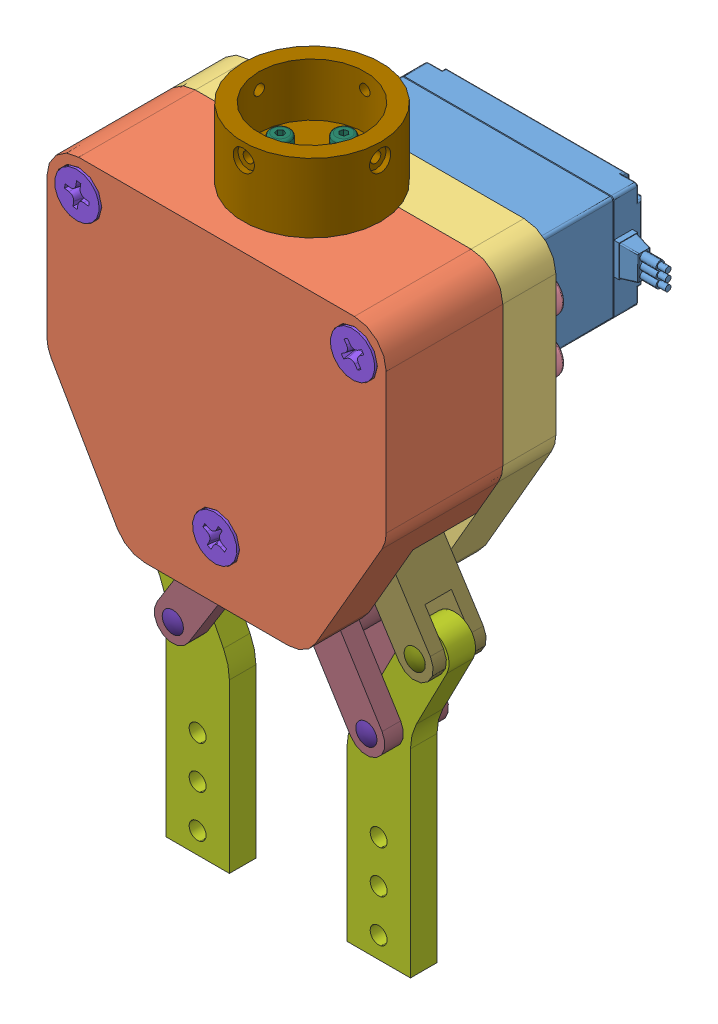
SolidWorks assembly Сборка схват, configuration По умолчанию. Lengths in mm.
Overall size (78.28 129.29 61.42).
45 component instances, 18 part files, 105 mates.
Components (placement in the parent):
- MG995-1: MG995 [По умолчанию] at origin size (55.5 20 44.57)
- Корпус 2-1: Корпус 2 [По умолчанию] at (-31.9999 21 61.0656) x (1 0 0) z (0 0 -1) size (64 60 22)
- 1-1: 1 [По умолчанию] at (32 21 29.0656) x (-1 0 0) z (0 0 1) size (64 60 10)
- DIN912-M4x12-1: DIN912-M4x12 [По умолчанию] at (-24 -5 22.8) x (0 0 1) z (-0.537932 -0.842988 0) size (16.28 7 7)
- DIN912-M4x12-2: DIN912-M4x12 [По умолчанию] at (24 5 22.8) x (0 0 1) z (-0.298401 0.954441 0) size (16.28 7 7)
- DIN912-M4x12-3: DIN912-M4x12 [По умолчанию] at (-24 5 22.8) x (0 0 1) z (-0.927261 0.374416 0) size (16.28 7 7)
- DIN912-M4x12-4: DIN912-M4x12 [По умолчанию] at (24 -5 22.8) x (0 0 1) z (-0.721763 -0.69214 0) size (16.28 7 7)
- DIN934-M4-2: DIN934-M4 [По умолчанию] at (-24 5 34.5656) size (7.43 8.21 3.68)
- DIN934-M4-3: DIN934-M4 [По умолчанию] at (24 5 34.5656) size (7.43 8.21 3.68)
- DIN934-M4-4: DIN934-M4 [По умолчанию] at (24 -5 34.5656) size (7.43 8.21 3.68)
- DIN934-M4-5: DIN934-M4 [По умолчанию] at (-24 -5 34.5656) size (7.43 8.21 3.68)
- DIN7 D5-L30-1: DIN7 D5-L30 [По умолчанию] at (12.0501 -18 33.0656) x (0 0 1) z (-0.049842 0.998757 0) size (24 5 5)
- DIN7 D5-L30-2: DIN7 D5-L30 [По умолчанию] at (-12.05 -18 33.0656) x (0 0 1) z (0.952169 -0.305572 0) size (24 5 5)
- 6_GRIPPER_ARM-1: 6_GRIPPER_ARM [По умолчанию] at (17.0771 -95.2932 47.5656) x (1 0 0) z (0 1 0) size (19.3 5 59)
- 6_GRIPPER_ARM-2: 6_GRIPPER_ARM [По умолчанию] at (-17.0771 -95.2932 42.5656) x (-1 0 0) z (0 1 0) size (19.3 5 59)
- DIN7046-1_M4x30-1: DIN7046-1_M4x30 [По умолчанию] at (26.0001 15 61.4156) x (0 0 -1) z (0.831237 0.555919 0) size (33.09 8.4 8.4)
- DIN7046-1_M4x30-2: DIN7046-1_M4x30 [По умолчанию] at (0 -28 61.4156) x (0 0 -1) z (0.888568 -0.458744 0) size (33.09 8.4 8.4)
- DIN7046-1_M4x30-3: DIN7046-1_M4x30 [По умолчанию] at (-26 15 61.4156) x (0 0 -1) z (0.988915 -0.148483 0) size (33.09 8.4 8.4)
- DIN934-M4-6: DIN934-M4 [По умолчанию] at (-26 15 29.0656) size (7.43 8.21 3.68)
- DIN934-M4-7: DIN934-M4 [По умолчанию] at (26 15 32.2656) x (0.467399 -0.884046 0) z (0 0 -1) size (7.43 8.21 3.68)
- DIN934-M4-8: DIN934-M4 [По умолчанию] at (0 -28 29.0656) size (7.43 8.21 3.68)
- ФланецСхват-1: ФланецСхват [По умолчанию] at (0.0001 34 43.0656) x (0 -1 0) z (1 0 0) size (13 26 26)
- втулка-2: втулка [По умолчанию] at (12.0501 -18 33.0656) x (0.999914 -0.013116 0) z (0 0 1) size (10 10 7)
- втулка-3: втулка [По умолчанию] at (-12.05 -18 57.0656) x (0.833208 -0.552959 0) z (0 0 -1) size (10 10 7)
- втулка-4: втулка [По умолчанию] at (12.0501 -18 57.0656) x (0.99444 0.105308 0) z (0 0 -1) size (10 10 7)
- втулка-6: втулка [По умолчанию] at (-12.05 -18 33.0656) x (0.948132 0.317878 0) z (0 0 1) size (10 10 7)
- ВалШестерня-3: ВалШестерня [Вал-шестерня] at (10 0 44.5) x (0 0 1) z (0.822261 0.56911 0) size (10 13.61 13.61)
- КолесоКривошип-1: КолесоКривошип [Колесо-кривошип] at (12.0501 -18 44.0656) x (0 0 1) z (0.841252 0.540643 0) size (10 42.92 25.84)
- КолесоКривошип-2: КолесоКривошип [Колесо-кривошип] at (-12.05 -18 44.0656) x (0 0 1) z (0.841251 -0.540644 0) size (10 42.92 25.84)
- Кривошип-1: Кривошип [По умолчанию] at (-21.2278 -54.2097 39.0656) x (0 0 1) z (-0.848527 0.529152 0) size (12 33 7)
- Кривошип-2: Кривошип [По умолчанию] at (15.2881 -57.9138 39.0656) x (0 0 1) z (-0.848528 -0.52915 0) size (12 33 7)
- gayka_m2-1: gayka_m2 [По умолчанию] at (0 13.4 37.0656) x (0.888267 0 -0.459328) z (0 1 0) size (4.25 4.76 2.06)
- gayka_m2-2: gayka_m2 [По умолчанию] at (0.0001 13.4 49.0656) x (0.888267 0 -0.459328) z (0 1 0) size (4.25 4.76 2.06)
- gayka_m2-3: gayka_m2 [По умолчанию] at (-5.9999 13.4 43.0656) x (0.888267 0 -0.459328) z (0 1 0) size (4.25 4.76 2.06)
- gayka_m2-5: gayka_m2 [По умолчанию] at (6.0001 13.4 43.0656) x (0.888267 0 -0.459328) z (0 1 0) size (4.25 4.76 2.06)
- DIN912-M2x12-1: DIN912-M2x12 [По умолчанию] at (6.0001 26 43.0656) x (0 -1 0) z (0.6502 0 0.759763) size (14.19 3.8 3.8)
- DIN912-M2x12-2: DIN912-M2x12 [По умолчанию] at (0.0001 26 37.0656) x (0 -1 0) z (0.733895 0 0.679263) size (14.19 3.8 3.8)
- DIN912-M2x12-3: DIN912-M2x12 [По умолчанию] at (-5.9999 26 43.0656) x (0 -1 0) z (0.223689 0 0.97466) size (14.19 3.8 3.8)
- DIN912-M2x12-4: DIN912-M2x12 [По умолчанию] at (0.0001 26 49.0656) x (0 -1 0) z (0.998157 0 0.060686) size (14.19 3.8 3.8)
- DIN7 D4-L10-1: DIN7 D4-L10 [По умолчанию] at (-26.3771 -40.2932 40.0656) x (0 0 1) z (-1 0 0) size (11.2 4 4)
- DIN7 D4-L10-2: DIN7 D4-L10 [По умолчанию] at (26.3771 -40.2932 40.0656) x (0 0 1) z (-1 0 0) size (11.2 4 4)
- DIN7 D4-L12-7: DIN7 D4-L12 [По умолчанию] at (-18.258 -56.0617 39.0656) x (0 0 1) z (-0.999999 0.001325 0) size (13.2 4 4)
- DIN7 D4-L12-8: DIN7 D4-L12 [По умолчанию] at (18.258 -56.0617 39.0656) x (0 0 1) z (-0.999999 0.001325 0) size (13.2 4 4)
- DIN7 D4-L24-1: DIN7 D4-L24 [По умолчанию] at (4.5001 -34 33.0656) x (0 0 1) z (0.845277 -0.534328 0) size (25.2 4 4)
- DIN7 D4-L24-2: DIN7 D4-L24 [По умолчанию] at (-4.5 -34 33.0656) x (0 0 1) z (-0.548806 -0.83595 0) size (25.2 4 4)
Mates (geometry in assembly coordinates):
- Концентричный5: concentric aligned: circle of MG995-1; circle of 1-1
- Концентричный6: concentric aligned: circle of MG995-1; circle of 1-1
- Концентричный13: concentric aligned: circle of DIN912-M4x12-3; circle of MG995-1
- Концентричный14: concentric aligned: circle of MG995-1; circle of DIN912-M4x12-2
- Концентричный16: concentric aligned: circle of MG995-1; circle of DIN912-M4x12-4
- Концентричный18: concentric anti-aligned: circle of 1-1; circle of DIN934-M4-2
- Совпадение19: coincident anti-aligned: plane of 1-1 through (32 21 34.5656) normal (0 0 1); plane of DIN934-M4-2 through (-24 5 34.5656) normal (0 0 -1)
- Параллельность4: parallel anti-aligned: plane of 1-1 through (-27.6 2.9215 34.5656) normal (1 0 0); plane of DIN934-M4-2 through (-27.5 6.9795 37.7656) normal (-1 0 0)
- Параллельность8: parallel anti-aligned: plane of 1-1 through (-27.6 -7.0785 34.5656) normal (1 0 0); plane of DIN934-M4-5 through (-27.5 -3.0205 37.7656) normal (-1 0 0)
- Совпадение32: coincident anti-aligned: plane of 1-1 through (32 21 34.5656) normal (0 0 1); plane of DIN934-M4-5 through (-24 -5 34.5656) normal (0 0 -1)
- Концентричный22: concentric anti-aligned: circle of 1-1; circle of DIN934-M4-5
- Концентричный23: concentric anti-aligned: cylinder of MG995-1 through (-24 -5 29) axis (0 0 -1) radius 2; circle of DIN912-M4x12-1
- Совпадение35: coincident anti-aligned: plane of 1-1 through (32 21 34.5656) normal (0 0 1); plane of DIN934-M4-3 through (24 5 34.5656) normal (0 0 -1)
- Концентричный24: concentric anti-aligned: circle of 1-1; circle of DIN934-M4-3
- Совпадение37: coincident anti-aligned: plane of 1-1 through (32 21 34.5656) normal (0 0 1); plane of DIN934-M4-4 through (24 -5 34.5656) normal (0 0 -1)
- Концентричный25: concentric anti-aligned: circle of 1-1; circle of DIN934-M4-4
- Параллельность11: parallel anti-aligned: plane of 1-1 through (27.6 7.0785 34.5656) normal (-1 0 0); plane of DIN934-M4-3 through (27.5 3.0205 37.7656) normal (1 0 0)
- Параллельность12: parallel anti-aligned: plane of 1-1 through (27.6 -2.9215 34.5656) normal (-1 0 0); plane of DIN934-M4-4 through (27.5 -6.9795 37.7656) normal (1 0 0)
- Совпадение47: coincident anti-aligned: plane of Корпус 2-1 through (-31.9999 21 39.0656) normal (0 0 -1); plane of 1-1 through (32 21 39.0656) normal (0 0 1)
- Концентричный31: concentric aligned: circle of Корпус 2-1; circle of 1-1
- Концентричный32: concentric aligned: circle of Корпус 2-1; circle of 1-1
- Концентричный33: concentric aligned: circle of Корпус 2-1; circle of DIN7046-1_M4x30-3
- Концентричный34: concentric aligned: circle of Корпус 2-1; circle of DIN7046-1_M4x30-2
- Концентричный35: concentric aligned: circle of Корпус 2-1; circle of DIN7046-1_M4x30-1
- Параллельность13: parallel anti-aligned: plane of 1-1 through (-22.4 17.0785 32.2656) normal (-1 0 0); plane of DIN934-M4-6 through (-22.5 13.0205 32.2656) normal (1 0 0)
- Концентричный36: concentric anti-aligned: circle of 1-1; circle of DIN934-M4-6
- Совпадение58: coincident anti-aligned: plane of 1-1 through (32 21 32.2656) normal (0 0 -1); plane of DIN934-M4-6 through (-26 15 32.2656) normal (0 0 1)
- Совпадение59: coincident anti-aligned: plane of 1-1 through (32 21 32.2656) normal (0 0 -1); plane of DIN934-M4-7 through (26 15 32.2656) normal (0 0 1)
- Концентричный38: concentric aligned: circle of 1-1; circle of DIN934-M4-7
- Параллельность14: parallel anti-aligned: plane of 1-1 through (29.6 17.0785 32.2656) normal (-1 0 0); plane of DIN934-M4-7 through (29.3859 16.7901 29.0656) normal (1 0 0)
- Совпадение62: coincident anti-aligned: plane of 1-1 through (32 21 32.2656) normal (0 0 -1); plane of DIN934-M4-8 through (0 -28 32.2656) normal (0 0 1)
- Концентричный39: concentric anti-aligned: circle of 1-1; circle of DIN934-M4-8
- Параллельность15: parallel anti-aligned: plane of 1-1 through (3.6 -25.9215 32.2656) normal (-1 0 0); plane of DIN934-M4-8 through (3.5 -29.9795 32.2656) normal (1 0 0)
- Концентричный56: concentric anti-aligned: cylinder of 1-1 through (-12.05 -18 39.0656) axis (0 0 1) radius 3.5; cylinder of DIN7 D5-L30-2 through (-12.05 -18 33.0656) axis (0 0 -1) radius 2.5
- Совпадение112: coincident anti-aligned: circle of MG995-1; circle of ВалШестерня-3
- Концентричный66: concentric anti-aligned: circle of 6_GRIPPER_ARM-2; circle of КолесоКривошип-2
- Концентричный71: concentric aligned: cylinder of 6_GRIPPER_ARM-1 through (26.3771 -40.2932 47.5656) axis (0 0 1) radius 2; cylinder of КолесоКривошип-1 through (26.3771 -40.2932 50.0656) axis (0 0 1) radius 2
- Совпадение118: coincident anti-aligned: plane of 6_GRIPPER_ARM-1 through (21.0771 -63.6799 47.5656) normal (0 0 1); plane of КолесоКривошип-1 through (18.481 -51.9056 47.5656) normal (0 0 -1)
- Совпадение120: coincident anti-aligned: plane of 1-1 through (32 21 39.0656) normal (0 0 1); plane of Кривошип-1 through (-18.258 -56.0617 39.0656) normal (0 0 -1)
- Концентричный74: concentric anti-aligned: circle of 6_GRIPPER_ARM-2; circle of Кривошип-1
- Совпадение125: coincident anti-aligned: plane of 1-1 through (32 21 39.0656) normal (0 0 1); plane of Кривошип-2 through (18.258 -56.0617 39.0656) normal (0 0 -1)
- Концентричный76: concentric aligned: circle of 6_GRIPPER_ARM-1; circle of Кривошип-2
- Концентричный77: concentric anti-aligned: circle of 6_GRIPPER_ARM-2; circle of КолесоКривошип-2
- Концентричный78: concentric anti-aligned: circle of 6_GRIPPER_ARM-2; circle of КолесоКривошип-2
- Параллельность18: parallel anti-aligned: plane of 6_GRIPPER_ARM-2 through (-21.0771 -63.6799 42.5656) normal (0 0 -1); plane of КолесоКривошип-2 through (-40.2203 -37.9345 42.5656) normal (0 0 1)
- Совпадение138: coincident anti-aligned: plane of Корпус 2-1 through (-31.9999 21 51.0656) normal (0 1 0); plane of ФланецСхват-1 through (0.0001 21 30.0656) normal (0 -1 0)
- Концентричный83: concentric aligned: circle of Корпус 2-1; circle of ФланецСхват-1
- Концентричный84: concentric aligned: circle of Корпус 2-1; circle of ФланецСхват-1
- Совпадение141: coincident anti-aligned: plane of 1-1 through (32 15 29.0656) normal (0 -1 0); plane of gayka_m2-1 through (0 15 37.0656) normal (0 1 0)
- Параллельность23: parallel aligned: plane of 1-1 through (-1.1547 15 35.0656) normal (0 0 1); plane of gayka_m2-1 through (-1.2594 15 38.9843) normal (0 0 1)
- Концентричный85: concentric aligned: circle of 1-1; circle of gayka_m2-1
- Совпадение153: coincident anti-aligned: circle of Корпус 2-1; circle of gayka_m2-3
- Параллельность24: parallel aligned: plane of Корпус 2-1 through (-4.8452 15 45.0656) normal (0 0 -1); plane of gayka_m2-3 through (-4.7405 15 41.147) normal (0 0 -1)
- Совпадение155: coincident anti-aligned: circle of Корпус 2-1; circle of gayka_m2-2
- Параллельность25: parallel aligned: plane of Корпус 2-1 through (-31.9999 21 51.0656) normal (0 0 -1); plane of gayka_m2-2 through (1.2595 15 47.147) normal (0 0 -1)
- Совпадение157: coincident anti-aligned: circle of Корпус 2-1; circle of gayka_m2-5
- Параллельность26: parallel aligned: plane of Корпус 2-1 through (7.1548 15 45.0656) normal (0 0 -1); plane of gayka_m2-5 through (7.2595 15 41.147) normal (0 0 -1)
- Концентричный86: concentric aligned: circle of ФланецСхват-1; circle of DIN912-M2x12-1
- Совпадение158: coincident anti-aligned: plane of ФланецСхват-1 through (0.0001 24 43.0656) normal (0 1 0); plane of DIN912-M2x12-1 through (7.4436 24 41.8302) normal (0 -1 0)
- Концентричный89: concentric aligned: circle of ФланецСхват-1; circle of DIN912-M2x12-4
- Совпадение160: coincident anti-aligned: plane of ФланецСхват-1 through (0.0001 24 43.0656) normal (0 1 0); plane of DIN912-M2x12-4 through (0.1154 24 47.1691) normal (0 -1 0)
- Концентричный90: concentric aligned: circle of ФланецСхват-1; circle of DIN912-M2x12-3
- Совпадение162: coincident anti-aligned: plane of ФланецСхват-1 through (0.0001 24 43.0656) normal (0 1 0); plane of DIN912-M2x12-3 through (-4.1481 24 42.6406) normal (0 -1 0)
- Концентричный91: concentric aligned: circle of ФланецСхват-1; circle of DIN912-M2x12-2
- Совпадение163: coincident anti-aligned: plane of ФланецСхват-1 through (0.0001 24 43.0656) normal (0 1 0); plane of DIN912-M2x12-2 through (1.2907 24 35.6712) normal (0 -1 0)
- Совпадение170: coincident aligned: cone of Корпус 2-1 through (-26 15 61.0656) axis (0 0 -1); cone of DIN7046-1_M4x30-3 through (-26 15 58.7156) axis (0 0 -1)
- Совпадение171: coincident aligned: cone of Корпус 2-1 through (26.0001 15 61.0656) axis (0 0 -1); cone of DIN7046-1_M4x30-1 through (26.0001 15 58.7156) axis (0 0 -1)
- Совпадение172: coincident aligned: cone of Корпус 2-1 through (0 -28 61.0656) axis (0 0 -1); cone of DIN7046-1_M4x30-2 through (0 -28 58.7156) axis (0 0 -1)
- Совпадение175: coincident anti-aligned: plane of MG995-1 through (20.2739 -0.7602 29.5885) normal (0.087156 0 0.996195); plane of 1-1 through (19.25 0.375 29.678) normal (-0.087156 0 -0.996195)
- Совпадение176: coincident aligned: circle of MG995-1; circle of DIN912-M4x12-2
- Совпадение177: coincident aligned: circle of MG995-1; circle of DIN912-M4x12-4
- Совпадение178: coincident aligned: circle of MG995-1; circle of DIN912-M4x12-3
- Совпадение179: coincident anti-aligned: plane of MG995-1 through (-20.3 -9.5 27) normal (0 0 -1); circle of DIN912-M4x12-1
- Концентричный92: concentric anti-aligned: cone of 1-1 through (12.0501 -18 33.0656) axis (0 0 -1); circle of втулка-2
- Совпадение180: coincident anti-aligned: plane of 1-1 through (32 21 39.0656) normal (0 0 1); plane of втулка-2 through (12.0501 -18 39.0656) normal (0 0 -1)
- Концентричный93: concentric anti-aligned: circle of 1-1; circle of втулка-6
- Совпадение181: coincident anti-aligned: plane of 1-1 through (32 21 39.0656) normal (0 0 1); plane of втулка-6 through (-12.05 -18 39.0656) normal (0 0 -1)
- Концентричный94: concentric anti-aligned: circle of DIN7 D5-L30-1; circle of втулка-2
- Совпадение182: coincident anti-aligned: circle of DIN7 D5-L30-1; circle of втулка-2
- Совпадение184: coincident anti-aligned: circle of DIN7 D5-L30-2; circle of втулка-6
- Концентричный95: concentric aligned: circle of втулка-2; circle of КолесоКривошип-1
- Концентричный96: concentric anti-aligned: circle of втулка-6; circle of КолесоКривошип-2
- Совпадение185: coincident anti-aligned: plane of втулка-2 through (12.0501 -18 40.0656) normal (0 0 1); plane of КолесоКривошип-1 through (12.0501 -18 40.0656) normal (0 0 -1)
- Совпадение186: coincident anti-aligned: plane of втулка-6 through (-12.05 -18 40.0656) normal (0 0 1); plane of КолесоКривошип-2 through (-12.05 -18 40.0656) normal (0 0 -1)
- Концентричный97: concentric aligned: circle of DIN7 D5-L30-1; cylinder of втулка-4 through (12.0501 -18 57.0656) axis (0 0 -1) radius 2.5
- Совпадение188: coincident anti-aligned: plane of втулка-4 through (12.0501 -18 50.0656) normal (0 0 -1); plane of КолесоКривошип-1 through (12.0501 -18 50.0656) normal (0 0 1)
- Концентричный98: concentric aligned: circle of DIN7 D5-L30-2; circle of втулка-3
- Совпадение190: coincident anti-aligned: plane of втулка-3 through (-12.05 -18 50.0656) normal (0 0 -1); plane of КолесоКривошип-2 through (-12.05 -18 50.0656) normal (0 0 1)
- Концентричный99: concentric anti-aligned: circle of КолесоКривошип-1; circle of DIN7 D4-L10-2
- Совпадение191: coincident anti-aligned: plane of КолесоКривошип-1 through (12.0501 -18 50.0656) normal (0 0 1); circle of DIN7 D4-L10-2
- Концентричный101: concentric anti-aligned: circle of КолесоКривошип-2; circle of DIN7 D4-L10-1
- Совпадение192: coincident anti-aligned: plane of КолесоКривошип-2 through (-12.05 -18 50.0656) normal (0 0 1); circle of DIN7 D4-L10-1
- Совпадение198: coincident anti-aligned: circle of 1-1; circle of DIN7 D4-L24-1
- Совпадение202: coincident anti-aligned: circle of 1-1; circle of DIN7 D4-L24-2
- Параллельность34: parallel aligned: line of 1-1 through (-13.5359 -39 39.0656) axis (1 0 0); line of 6_GRIPPER_ARM-1 through (11.0771 -95.2932 47.5656) axis (1 0 0)
- Параллельность35: parallel anti-aligned: line of 1-1 through (-13.5359 -39 39.0656) axis (1 0 0); line of 6_GRIPPER_ARM-2 through (-11.0771 -95.2932 47.5656) axis (-1 0 0)
- Симметричный5: symmetric: point of 6_GRIPPER_ARM-1; point of 6_GRIPPER_ARM-2; plane of assembly
- Концентричный106: concentric anti-aligned: circle of Кривошип-1; circle of DIN7 D4-L24-2
- Совпадение221: coincident anti-aligned: plane of 1-1 through (32 21 39.0656) normal (0 0 1); plane of Кривошип-2 through (18.258 -56.0617 39.0656) normal (0 0 -1)
- Совпадение222: coincident anti-aligned: plane of 1-1 through (32 21 39.0656) normal (0 0 1); plane of Кривошип-2 through (18.258 -56.0617 39.0656) normal (0 0 -1)
- Концентричный110: concentric anti-aligned: circle of 6_GRIPPER_ARM-2; circle of Кривошип-1
- Совпадение226: coincident anti-aligned: circle of Кривошип-1; circle of DIN7 D4-L12-7
- Концентричный111: concentric anti-aligned: circle of Кривошип-2; circle of DIN7 D4-L24-1
- Концентричный112: concentric aligned: circle of 6_GRIPPER_ARM-1; circle of Кривошип-2
- Совпадение230: coincident anti-aligned: circle of Кривошип-2; circle of DIN7 D4-L12-8
